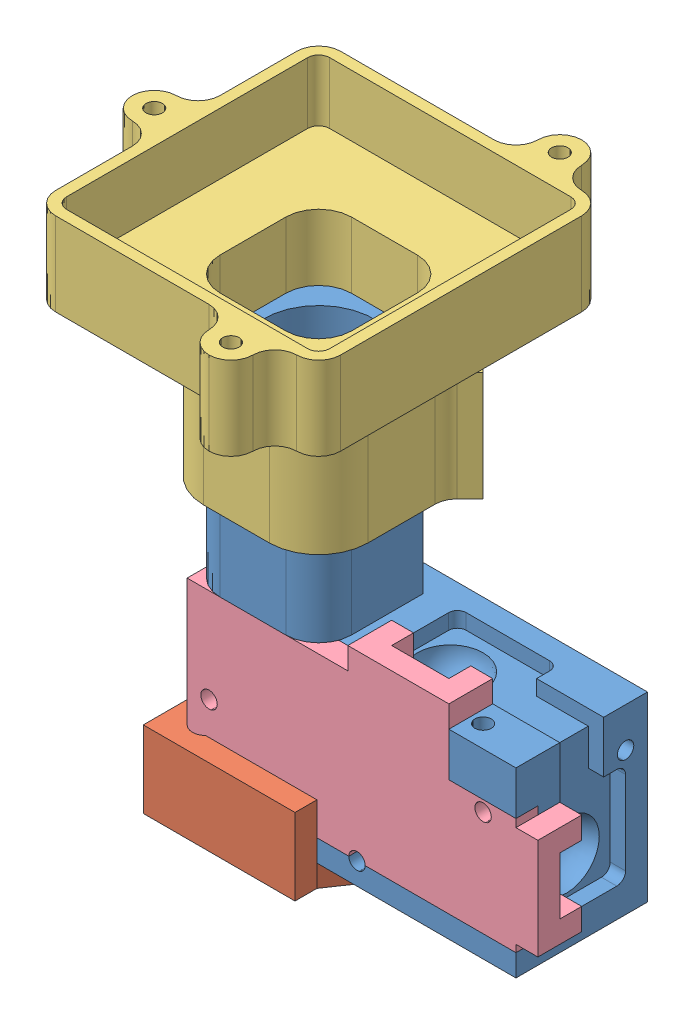
SolidWorks assembly OptoGscope_v1_0.2_Assembled, configuration Default. Lengths in mm.
Overall size (21.5 24.11 17).
4 component instances, 4 part files, 9 mates.
Components (placement in the parent):
- OGS_MainBodyv1_0.2-1: OGS_MainBodyv1_0.2 [Default] at (0.3631 0.3984 16.4815) size (15 17.3 6)
- MS_Baseplatev3-1: MS_Baseplatev3 [Default] at (-2.3869 -0.6016 16.2315) x (0 0 1) z (-1 0 0) size (9.02 3.5 12.54)
- MS_FocusSliderv3.2-1: MS_FocusSliderv3.2 [Default] at (-4.1369 12.71 16.4815) size (15 10.8 17)
- FilterCoverV5-2: FilterCoverV5 [Default] at (2.2685 4.8848 19.4815) x (-1 0 0) z (0 0 -1) size (16 8.3 2)
Mates (geometry in assembly coordinates):
- Concentric6: concentric anti-aligned: cylinder of OGS_MainBodyv1_0.2-1 through (6.3631 6.1984 19.4815) axis (0 0 -1) radius 0.375; cylinder of FilterCoverV5-2 through (6.3631 6.1984 18.4815) axis (0 0 1) radius 0.375
- Concentric7: concentric anti-aligned: cylinder of OGS_MainBodyv1_0.2-1 through (-6.1369 4.3984 19.4815) axis (0 0 -1) radius 0.375; cylinder of FilterCoverV5-2 through (-6.1369 4.3984 18.4815) axis (0 0 1) radius 0.375
- Concentric8: concentric anti-aligned: cylinder of OGS_MainBodyv1_0.2-1 through (0.6131 1.3984 19.4815) axis (0 0 -1) radius 0.375; cylinder of FilterCoverV5-2 through (0.6131 1.3984 18.4815) axis (0 0 1) radius 0.375
- Coincident1: coincident anti-aligned: plane of OGS_MainBodyv1_0.2-1 through (0.3631 0.3984 18.4815) normal (0 0 1); plane of FilterCoverV5-2 through (2.2685 4.8848 18.4815) normal (0 0 -1)
- Coincident3: coincident: plane of OGS_MainBodyv1_0.2-1 through (7.8631 8.6984 19.4815) normal (0 0 1); plane of MS_Baseplatev3-1 through (2.3631 -12.7492 19.4815) normal (0 0 -1)
- Coincident4: coincident: plane of OGS_MainBodyv1_0.2-1 through (-7.1369 8.6984 13.4815) normal (-1 0 0); plane of MS_Baseplatev3-1 through (-7.1369 -12.7492 19.4815) normal (1 0 0)
- Concentric9: concentric aligned: cylinder of OGS_MainBodyv1_0.2-1 through (-5.6369 6.577 17.9815) axis (0 1 0) radius 1.5; cylinder of MS_FocusSliderv3.2-1 through (-5.6369 23.51 17.9815) axis (0 1 0) radius 1.5
- Concentric10: concentric anti-aligned: cylinder of OGS_MainBodyv1_0.2-1 through (-5.6369 8.6984 14.9815) axis (0 -1 0) radius 1.5; cylinder of MS_FocusSliderv3.2-1 through (-5.6369 23.51 14.9815) axis (0 1 0) radius 1.5
- Coincident5: coincident anti-aligned: plane of OGS_MainBodyv1_0.2-1 through (0.3631 0.3984 16.4815) normal (0 -1 0); plane of MS_Baseplatev3-1 through (-2.3869 0.3984 16.2315) normal (0 1 0)
